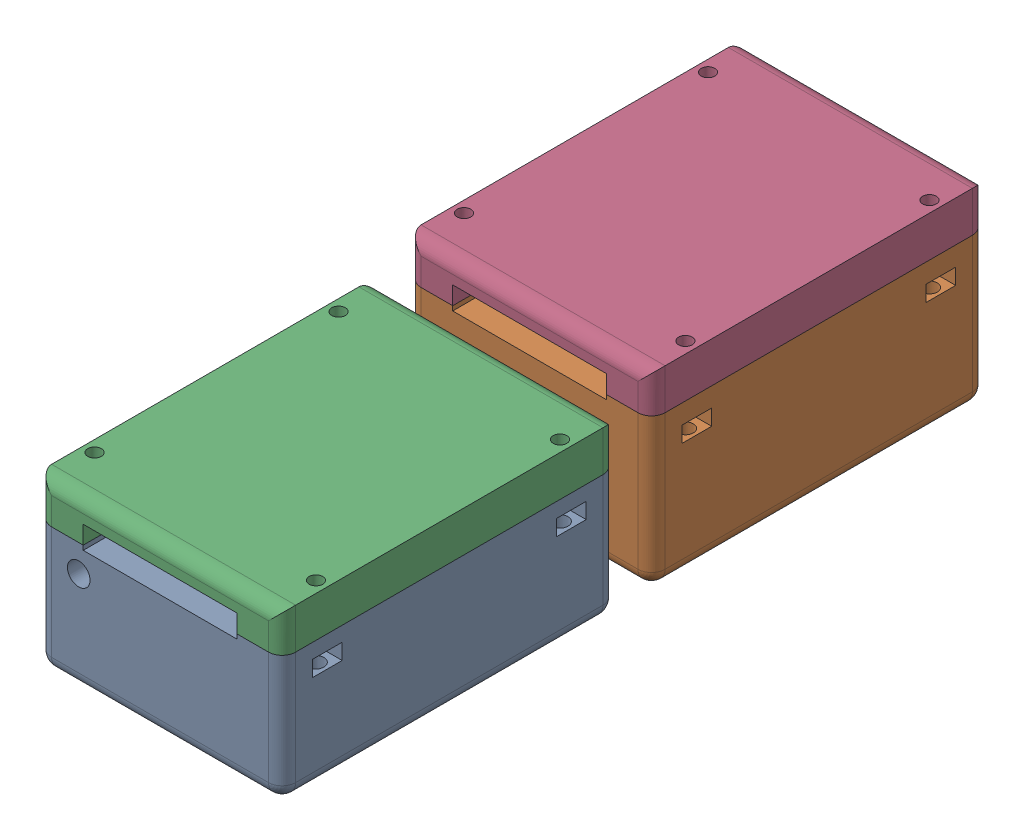
SolidWorks assembly Montagem versões da coleira, configuration Valor predeterminado. Lengths in mm.
Overall size (54 42 155.76).
4 component instances, 3 part files, 8 mates.
Components (placement in the parent):
- Coleira - Sensores (Ajustado v2)-1: Coleira - Sensores (Ajustado v2) [Valor predeterminado] at (-28.0033 -15.2465 1000) size (54 28 74)
- Coleira - Sensores-1: Coleira - Sensores [Valor predeterminado] at (-28.0033 -15.2465 918.2431) size (54 33 74)
- Coleira - Tampa-1: Coleira - Tampa [Valor predeterminado] at (-28.0033 21.7535 1000) x (-1 0 0) z (0 0 1) size (54 9 74)
- Coleira - Tampa-2: Coleira - Tampa [Valor predeterminado] at (-28.0033 26.7535 918.2431) x (1 0 0) z (0 0 -1) size (54 9 74)
Mates (geometry in assembly coordinates):
- Coincidente7: coincident aligned: plane of Coleira - Tampa (Ajustado v2)-1 through (-55.0033 -12.2465 1037) normal (-1 0 0); plane of Coleira - Tampa-1 through (-55.0033 16.7535 1037) normal (-1 0 0)
- Coincidente8: coincident anti-aligned: plane of Coleira - Tampa (Ajustado v2)-1 through (-28.0033 12.7535 1000) normal (0 1 0); plane of Coleira - Tampa-1 through (-28.0033 12.7535 1000) normal (0 -1 0)
- Coincidente9: coincident aligned: plane of Coleira - Tampa (Ajustado v2)-1 through (-55.0033 -12.2465 1037) normal (0 0 1); plane of Coleira - Tampa-1 through (-1.0033 16.7535 1037) normal (0 0 1)
- Coincidente10: coincident: point of Coleira - Sensores-1; plane of Coleira - Tampa-2 through (-28.0033 17.7535 918.2431) normal (0 -1 0)
- Coincidente12: coincident aligned: plane of Coleira - Sensores-1 through (-55.0033 -12.2465 955.2431) normal (-1 0 0); plane of Coleira - Tampa-2 through (-55.0033 21.7535 881.2431) normal (-1 0 0)
- Coincidente13: coincident aligned: plane of Coleira - Sensores-1 through (-55.0033 -12.2465 881.2431) normal (0 0 -1); plane of Coleira - Tampa-2 through (-55.0033 21.7535 881.2431) normal (0 0 -1)
- Coincidente14: coincident aligned: plane of Coleira - Tampa (Ajustado v2)-1 through (-28.0033 -15.2465 1000) normal (0 -1 0); plane of Coleira - Sensores-1 through (-28.0033 -15.2465 918.2431) normal (0 -1 0)
- Coincidente15: coincident aligned: plane of Coleira - Tampa (Ajustado v2)-1 through (-55.0033 -12.2465 1037) normal (-1 0 0); plane of Coleira - Sensores-1 through (-55.0033 -12.2465 955.2431) normal (-1 0 0)
